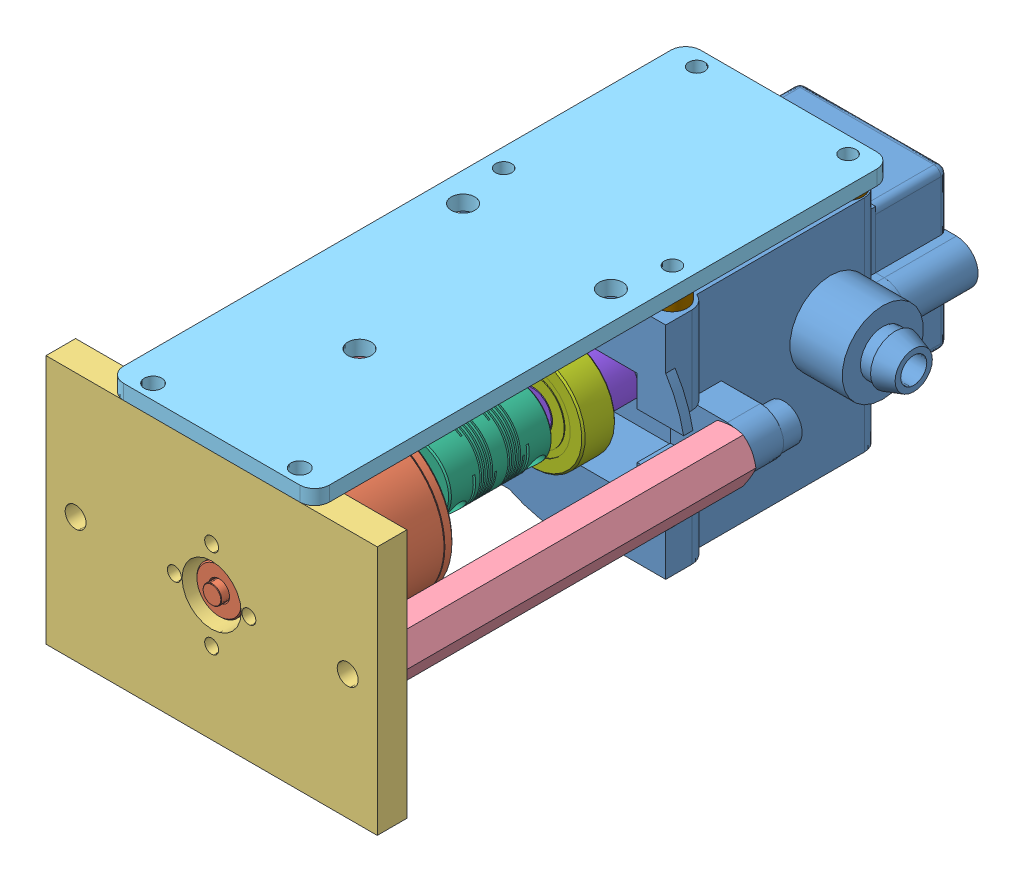
SolidWorks assembly Pump Assembly, configuration Default. Lengths in mm.
Overall size (80.47 56.31 145.43).
13 component instances, 9 part files, 31 mates.
Components (placement in the parent):
- Small Hydraulic Pump Head-1: Small Hydraulic Pump Head [Default] at (30.3425 31.0707 69.0301) size (80.47 52.61 70.05)
- Blue Robotics M100-1: Blue Robotics M100 [Default] at (21.91 55.1423 161.5555) x (-0.707107 0.707107 0) z (-0.707107 -0.707107 0) size (32 54 32)
- motor board-1: motor board [Default] at (30.3425 54.8117 163.3101) size (71.11 43.4 6.35)
- 91780A307 (Standoff)-1: 91780A307 (Standoff) [91780A307] at (59.5475 54.7207 125.2101) x (0.866025 0.5 0) z (0 0 1) size (9.53 11 77.29)
- 91780A307 (Standoff)-2: 91780A307 (Standoff) [91780A307] at (1.1375 54.7207 125.2101) x (0.866025 -0.5 0) z (0 0 1) size (9.53 11 77.29)
- Sheet strength plate-1: Sheet strength plate [Default] at (43.0675 81.5457 69.1254) size (44.2 3.17 123.88)
- 4mm-5mm flexable coupling-1: 4mm-5mm flexable coupling [2463K18] at (30.3425 54.8117 114.9976) x (0 -1 0) z (0 0 1) size (15.77 15.69 22)
- 8mm 5972K222-1: 8mm 5972K222 [5972K222] at (30.3425 54.8117 97.3226) x (-0.745781 0.666191 0) z (0 0 1) size (22 22 7)
- Impeller-1: Impeller [Default] at (30.3425 54.8117 93.8226) x (1 0 0) z (0 1 0) size (18 14 13.1)
- 94639A.25 .125 #8287-1: 94639A.25 .125 #8287 [94639A287] at (12.2323 79.9582 88.8633) x (1 0 0) z (0 1 0) size (6.35 6.35 3.17)
- 94639A.25 .125 #8287-2: 94639A.25 .125 #8287 [94639A287] at (46.5925 79.9582 49.2801) x (1 0 0) z (0 1 0) size (6.35 6.35 3.17)
- 94639A.25 .125 #8287-3: 94639A.25 .125 #8287 [94639A287] at (48.4527 79.9582 88.8633) x (1 0 0) z (0 1 0) size (6.35 6.35 3.17)
- 94639A.25 .125 #8287-4: 94639A.25 .125 #8287 [94639A287] at (14.0925 79.9582 49.2801) x (1 0 0) z (0 1 0) size (6.35 6.35 3.17)
Mates (geometry in assembly coordinates):
- Concentric1: concentric anti-aligned: circle of Small Hydraulic Pump Head-1; cylinder of Blue Robotics M100-1 through (30.3425 54.8117 169.5851) axis (0 0 -1) radius 2
- Concentric2: concentric aligned: cylinder of Blue Robotics M100-1 through (30.3425 54.8117 168.0601) axis (0 0 -1) radius 5; cylinder of motor board-1 through (30.3425 54.8117 169.6601) axis (0 0 -1) radius 6.35
- Parallel2: parallel aligned: plane of Small Hydraulic Pump Head-1 through (48.8079 78.3707 88.6801) normal (0 1 0); plane of motor board-1 through (-5.2125 81.5457 169.6601) normal (0 1 0)
- Concentric8: concentric anti-aligned: cylinder of Small Hydraulic Pump Head-1 through (59.5475 54.7207 76.0101) axis (0 0 1) radius 3.925; circle of 91780A307 (Standoff)-1
- Parallel5: parallel aligned: plane of Small Hydraulic Pump Head-1 through (48.8079 78.3707 88.6801) normal (0 1 0); plane of 91780A307 (Standoff)-1 through (62.2971 59.4832 163.3101) normal (0 1 0)
- Parallel6: parallel aligned: plane of Small Hydraulic Pump Head-1 through (48.8079 78.3707 88.6801) normal (0 1 0); plane of 91780A307 (Standoff)-2 through (3.8871 59.4832 163.3101) normal (0 1 0)
- Concentric9: concentric anti-aligned: cylinder of Small Hydraulic Pump Head-1 through (1.1375 54.7207 76.0101) axis (0 0 1) radius 3.925; circle of 91780A307 (Standoff)-2
- Coincident22: coincident anti-aligned: plane of Blue Robotics M100-1 through (26.0999 59.0543 163.3101) normal (0 0 1); plane of motor board-1 through (30.3425 54.8117 163.3101) normal (0 0 -1)
- Width2: width aligned: plane of Sheet strength plate-1 through (8.2425 84.7207 69.1254) normal (-1 0 0); plane of Sheet strength plate-1 through (52.4425 84.7207 69.1254) normal (1 0 0); plane of Small Hydraulic Pump Head-1 through (10.5925 78.3707 85.2801) normal (-1 0 0); plane of Small Hydraulic Pump Head-1 through (50.0925 78.3707 85.2801) normal (1 0 0)
- Coincident23: coincident aligned: plane of Small Hydraulic Pump Head-1 through (50.0925 78.3707 45.7801) normal (0 0 -1); plane of Sheet strength plate-1 through (43.0675 84.7207 45.7801) normal (0 0 -1)
- Coincident24: coincident anti-aligned: plane of motor board-1 through (-5.2125 81.5457 169.6601) normal (0 1 0); plane of Sheet strength plate-1 through (43.0675 81.5457 69.1254) normal (0 -1 0)
- Concentric10: concentric aligned: cylinder of Blue Robotics M100-1 through (30.3425 54.8117 169.5851) axis (0 0 -1) radius 2; cylinder of 4mm-5mm flexable coupling-1 through (30.3425 54.8117 125.9976) axis (0 0 -1) radius 2.5
- Distance3: distance = 1.5875 mm anti-aligned: plane of 4mm-5mm flexable coupling-1 through (30.3425 54.8117 125.9976) normal (0 0 1); plane of Blue Robotics M100-1 through (30.3425 54.8117 127.5851) normal (0 0 -1)
- Coincident25: coincident anti-aligned: plane of Small Hydraulic Pump Head-1 through (30.3425 31.0707 87.1101) normal (0 0 1); plane of 91780A307 (Standoff)-2 through (3.8871 59.4832 87.1101) normal (0 0 -1)
- Coincident26: coincident anti-aligned: plane of Small Hydraulic Pump Head-1 through (30.3425 31.0707 87.1101) normal (0 0 1); plane of 91780A307 (Standoff)-1 through (56.7979 59.4832 87.1101) normal (0 0 -1)
- Coincident27: coincident anti-aligned: plane of motor board-1 through (30.3425 54.8117 163.3101) normal (0 0 -1); plane of 91780A307 (Standoff)-1 through (56.7979 59.4832 163.3101) normal (0 0 1)
- Coincident28: coincident anti-aligned: plane of 8mm 5972K222-1 through (27.4446 51.5676 93.8226) normal (0 0 -1); plane of Impeller-1 through (30.3425 54.8117 93.8226) normal (0 0 1)
- Concentric11: concentric aligned: cylinder of 8mm 5972K222-1 through (30.3425 54.8117 100.8226) axis (0 0 1) radius 4; cylinder of Impeller-1 through (30.3425 54.8117 86.8226) axis (0 0 1) radius 4.1
- Concentric12: concentric anti-aligned: cylinder of Blue Robotics M100-1 through (30.3425 54.8117 169.5851) axis (0 0 -1) radius 2; cylinder of 8mm 5972K222-1 through (30.3425 54.8117 100.8226) axis (0 0 1) radius 11
- Distance4: distance = 3.175 mm anti-aligned: plane of 8mm 5972K222-1 through (23.2476 46.8691 100.8226) normal (0 0 1); plane of 4mm-5mm flexable coupling-1 through (30.3425 54.8117 103.9976) normal (0 0 -1)
- Concentric17: concentric anti-aligned: cylinder of Small Hydraulic Pump Head-1 through (14.0925 78.3707 49.2801) axis (0 1 0) radius 1.2891; cylinder of 94639A.25 .125 #8287-4 through (14.0925 81.5457 49.2801) axis (0 -1 0) radius 2.1082
- Concentric18: concentric anti-aligned: circle of Small Hydraulic Pump Head-1; cylinder of 94639A.25 .125 #8287-2 through (46.5925 81.5457 49.2801) axis (0 -1 0) radius 2.1082
- Concentric19: concentric anti-aligned: cylinder of Small Hydraulic Pump Head-1 through (48.4527 78.3707 88.8633) axis (0 1 0) radius 1.2891; cylinder of 94639A.25 .125 #8287-3 through (48.4527 81.5457 88.8633) axis (0 -1 0) radius 2.1082
- Concentric20: concentric anti-aligned: cylinder of Small Hydraulic Pump Head-1 through (12.2323 78.3707 88.8633) axis (0 1 0) radius 1.2891; cylinder of 94639A.25 .125 #8287-1 through (12.2323 81.5457 88.8633) axis (0 -1 0) radius 2.1082
- Coincident29: coincident aligned: plane of 94639A.25 .125 #8287-2 through (46.5925 81.5457 49.2801) normal (0 1 0); plane of 94639A.25 .125 #8287-3 through (48.4527 81.5457 88.8633) normal (0 1 0)
- Coincident30: coincident aligned: plane of 94639A.25 .125 #8287-1 through (12.2323 81.5457 88.8633) normal (0 1 0); plane of 94639A.25 .125 #8287-3 through (48.4527 81.5457 88.8633) normal (0 1 0)
- Coincident31: coincident aligned: plane of 94639A.25 .125 #8287-1 through (12.2323 81.5457 88.8633) normal (0 1 0); plane of 94639A.25 .125 #8287-4 through (14.0925 81.5457 49.2801) normal (0 1 0)
- Coincident32: coincident anti-aligned: plane of Small Hydraulic Pump Head-1 through (48.8079 78.3707 88.6801) normal (0 1 0); plane of 94639A.25 .125 #8287-2 through (46.5925 78.3707 49.2801) normal (0 -1 0)
- Concentric21: concentric anti-aligned: cylinder of Blue Robotics M100-1 through (30.3425 45.3117 139.8101) axis (0 0 1) radius 1.5; cylinder of motor board-1 through (30.3425 45.3117 169.6601) axis (0 0 -1) radius 1.5
- Parallel7: parallel aligned: plane of Small Hydraulic Pump Head-1 through (8.2425 78.3707 92.2801) normal (-1 0 0); plane of 4mm-5mm flexable coupling-1 through (30.6425 61.5617 109.0014) normal (-1 0 0)
- Parallel8: parallel aligned: plane of Small Hydraulic Pump Head-1 through (48.8079 31.0707 88.6801) normal (0 -1 0); plane of Impeller-1 through (32.8425 55.8117 100.8226) normal (0 -1 0)
